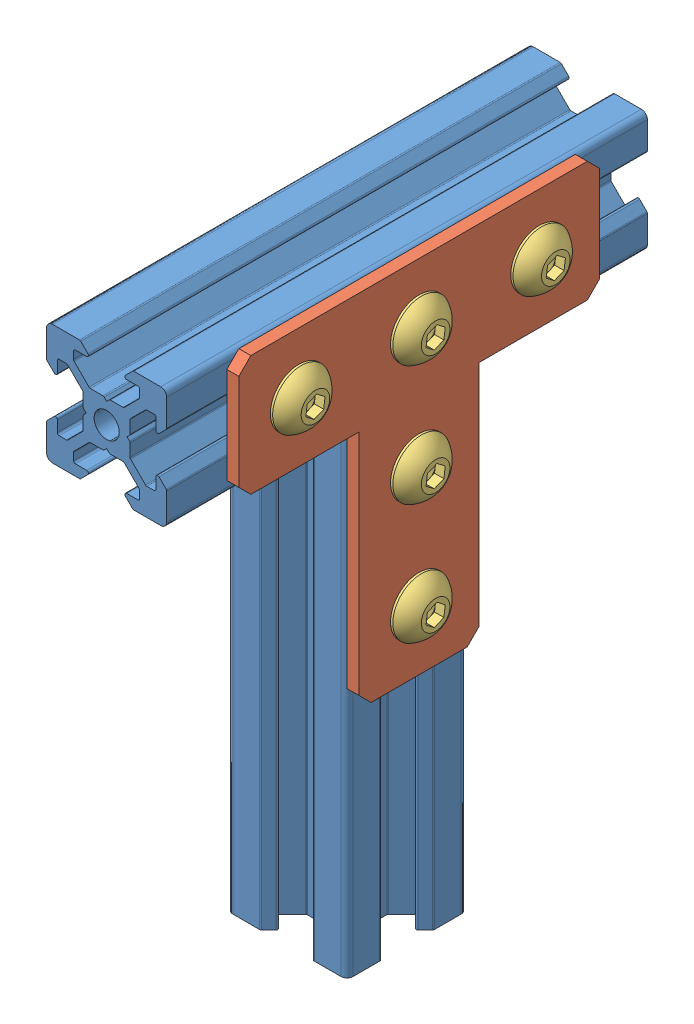
SolidWorks assembly Т-пластина 20 серия 3х3 5отв 60х60х2 СБ, configuration По умолчанию. Lengths in mm.
Overall size (24.75 100 80).
8 component instances, 3 part files, 16 mates.
Components (placement in the parent):
- 2020100-1: 2020100 [По умолчанию] at origin size (20 20 80)
- 2020100-2: 2020100 [По умолчанию] at (0 -90 40) x (1 0 0) z (0 1 0) size (20 20 80)
- Т-пластина 20 серия 3х3 5отв 60х60х2-1: Т-пластина 20 серия 3х3 5отв 60х60х2 [По умолчанию] at (10 -50 40) x (0 0 -1) z (0 -1 0) size (60 2 60)
- socket button head screw_iso-5: socket button head screw_iso [ISO 7380 - M5 x 10 - 10N] at (14.75 0 60) x (-1 0 0) z (0 0.924225 0.381849) size (12.75 9.5 9.5)
- socket button head screw_iso-6: socket button head screw_iso [ISO 7380 - M5 x 10 - 10N] at (14.75 0 20) x (-1 0 0) z (0 0.924225 0.381849) size (12.75 9.5 9.5)
- socket button head screw_iso-7: socket button head screw_iso [ISO 7380 - M5 x 10 - 10N] at (14.75 -20 40) x (-1 0 0) z (0 0.924225 0.381849) size (12.75 9.5 9.5)
- socket button head screw_iso-8: socket button head screw_iso [ISO 7380 - M5 x 10 - 10N] at (14.75 -40 40) x (-1 0 0) z (0 0.924225 0.381849) size (12.75 9.5 9.5)
- socket button head screw_iso-9: socket button head screw_iso [ISO 7380 - M5 x 10 - 10N] at (14.75 0 40) x (-1 0 0) z (0 0.924225 0.381849) size (12.75 9.5 9.5)
Mates (geometry in assembly coordinates):
- Совпадение1: coincident aligned: plane of 2020100-1 through (10 -10 80) normal (1 0 0); plane of 2020100-2 through (10 -10 30) normal (1 0 0)
- Совпадение2: coincident anti-aligned: plane of 2020100-1 through (10 -10 80) normal (0 -1 0); plane of 2020100-2 through (0 -10 40) normal (0 1 0)
- Расстояние1: distance = 30 mm aligned: plane of 2020100-2 through (-10 -10 50) normal (0 0 1); plane of 2020100-1 through (0 0 80) normal (0 0 1)
- Совпадение3: coincident anti-aligned: plane of 2020100-1 through (10 -10 80) normal (1 0 0); plane of Т-пластина 20 серия 2х3 4отв 40х60х2 усил.-1 through (10 -50 40) normal (-1 0 0)
- Совпадение4: coincident aligned: plane of 2020100-1 through (10 10 80) normal (0 1 0); plane of Т-пластина 20 серия 2х3 4отв 40х60х2 усил.-1 through (12 10 70) normal (0 1 0)
- Концентричный1: concentric aligned: cylinder of Т-пластина 20 серия 2х3 4отв 40х60х2 усил.-1 through (12 0 60) axis (1 0 0) radius 2.75; cylinder of socket button head screw_iso-5 through (14.75 0 60) axis (1 0 0) radius 4.75
- Совпадение6: coincident anti-aligned: plane of Т-пластина 20 серия 2х3 4отв 40х60х2 усил.-1 through (12 -50 40) normal (1 0 0); plane of socket button head screw_iso-5 through (12 -0.9546 62.3106) normal (-1 0 0)
- Концентричный2: concentric aligned: cylinder of Т-пластина 20 серия 2х3 4отв 40х60х2 усил.-1 through (12 0 20) axis (1 0 0) radius 2.75; cylinder of socket button head screw_iso-6 through (14.75 0 20) axis (1 0 0) radius 4.75
- Совпадение7: coincident anti-aligned: plane of Т-пластина 20 серия 2х3 4отв 40х60х2 усил.-1 through (12 -50 40) normal (1 0 0); plane of socket button head screw_iso-6 through (12 -0.9546 22.3106) normal (-1 0 0)
- Концентричный3: concentric aligned: cylinder of Т-пластина 20 серия 2х3 4отв 40х60х2 усил.-1 through (12 -20 40) axis (1 0 0) radius 2.75; cylinder of socket button head screw_iso-7 through (14.75 -20 40) axis (1 0 0) radius 4.75
- Совпадение8: coincident anti-aligned: plane of Т-пластина 20 серия 2х3 4отв 40х60х2 усил.-1 through (12 -50 40) normal (1 0 0); plane of socket button head screw_iso-7 through (12 -20.9546 42.3106) normal (-1 0 0)
- Концентричный4: concentric aligned: cylinder of Т-пластина 20 серия 2х3 4отв 40х60х2 усил.-1 through (12 -40 40) axis (1 0 0) radius 2.75; cylinder of socket button head screw_iso-8 through (14.75 -40 40) axis (1 0 0) radius 4.75
- Совпадение9: coincident anti-aligned: plane of Т-пластина 20 серия 2х3 4отв 40х60х2 усил.-1 through (12 -50 40) normal (1 0 0); plane of socket button head screw_iso-8 through (12 -40.9546 42.3106) normal (-1 0 0)
- Совпадение10: coincident aligned: plane of 2020100-2 through (10 -10 50) normal (0 0 1); plane of Т-пластина 20 серия 3х3 5отв 60х60х2-1 through (12 -10 50) normal (0 0 1)
- Концентричный5: concentric aligned: cylinder of Т-пластина 20 серия 3х3 5отв 60х60х2-1 through (12 0 40) axis (1 0 0) radius 2.75; cylinder of socket button head screw_iso-9 through (14.75 0 40) axis (1 0 0) radius 4.75
- Совпадение11: coincident anti-aligned: plane of Т-пластина 20 серия 3х3 5отв 60х60х2-1 through (12 -50 40) normal (1 0 0); plane of socket button head screw_iso-9 through (12 -0.9546 42.3106) normal (-1 0 0)
